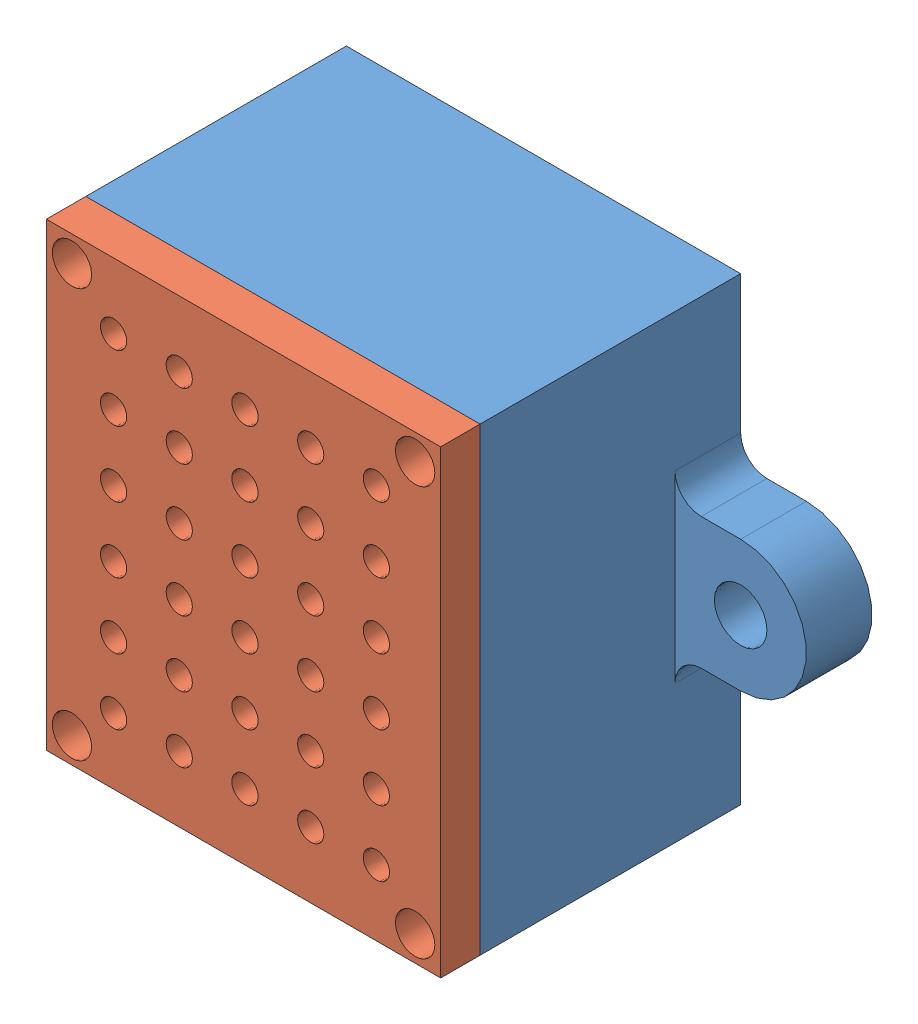
SolidWorks assembly Ass boite capteur, configuration Défaut. Lengths in mm.
Overall size (50 35.18 23).
2 component instances, 2 part files, 2 mates.
Components (placement in the parent):
- Boite capteur-1: Boite capteur [Défaut] at (-2.9834 -2.2534 50) size (50 35 20)
- Boite capteur couvercle-1: Boite capteur couvercle [Défaut] at (-2.8066 -2.0766 70) size (30 35 5)
Mates (geometry in assembly coordinates):
- Coïncidente1: coincident anti-aligned: plane of Boite capteur-1 through (-2.9834 -2.2534 70) normal (0 0 1); plane of Boite capteur couvercle-1 through (-2.8066 -2.0766 70) normal (0 0 -1)
- Coaxiale1: concentric aligned: cylinder of Boite capteur couvercle-1 through (-15.8621 -17.6321 68) axis (0 0 1) radius 1.5; cylinder of Boite capteur-1 through (-15.8621 -17.6321 60) axis (0 0 1) radius 1
